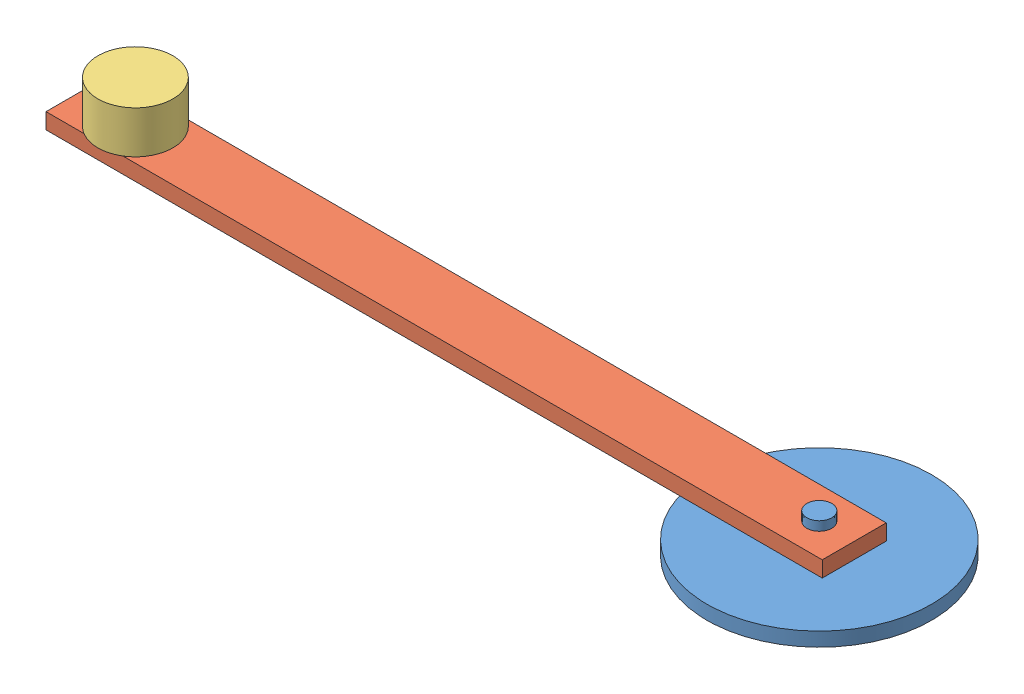
SolidWorks assembly assembly1, configuration Default. Lengths in mm.
Overall size (342 38.34 90).
3 component instances, 3 part files, 9 mates.
Components (placement in the parent):
- disc-1: disc [Default] at (274 -26.14 0) size (90 25 90)
- link-1: link [Default] at (132.5 -23.34 0) size (311 6.34 25.64)
- pulley-1: pulley [Default] x (1 0 0) z (0 0 -1) size (30 17 30)
Mates (geometry in assembly coordinates):
- Coincident1: coincident anti-aligned: plane of link-1 through (132.5 -17 79.9832) normal (0 1 0); plane of pulley-1 through (0 -17 79.9832) normal (0 -1 0)
- Coincident2: coincident anti-aligned: plane of link-1 through (132.5 -23.34 79.9832) normal (0 0 1); plane of pulley-1 through (0 0 79.9832) normal (0 0 -1)
- Distance1: distance = 23 mm anti-aligned: plane of pulley-1; plane of link-1 through (-23 -17 -12.82) normal (-1 0 0)
- Coincident4: coincident anti-aligned: plane of disc-1 through (274 -23.34 79.9832) normal (0 1 0); plane of link-1 through (132.5 -23.34 79.9832) normal (0 -1 0)
- Coincident5: coincident aligned: plane of disc-1 through (274 -26.14 79.9832) normal (0 0 1); plane of link-1 through (132.5 -23.34 79.9832) normal (0 0 1)
- Distance2: distance = 14 mm aligned: plane of disc-1 through (274 -26.14 0) normal (1 0 0); plane of link-1 through (288 -17 -12.82) normal (1 0 0)
- Coincident8: coincident: plane of pulley-1 through (0 0 0) normal (0 1 0); point of assembly
- Coincident9: coincident: plane of pulley-1; point of assembly
- Coincident10: coincident: plane of pulley-1 through (0 0 0) normal (0 0 -1); point of assembly
